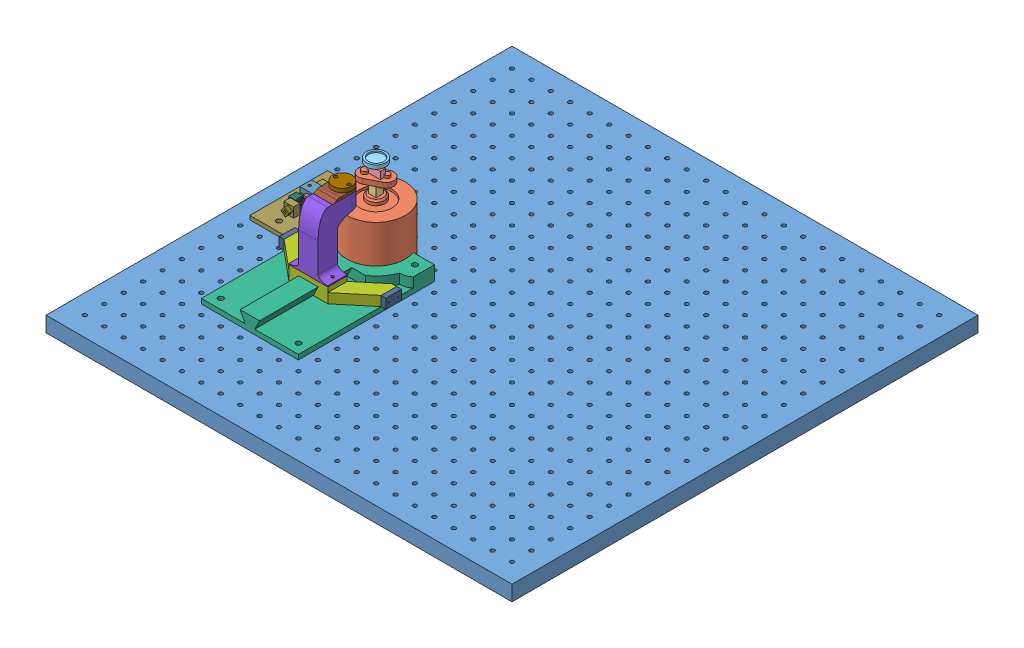
SolidWorks assembly TestAssem, configuration Default. Lengths in mm.
Overall size (609.6 135.55 609.6).
17 component instances, 16 part files, 44 mates.
Components (placement in the parent):
- ThorLabs Table-1: ThorLabs Table [Default] at (-195.0438 -27.549 258.8057) size (609.6 20 609.6)
- Mock Actuator-1: Mock Actuator [Default] at (-42.6438 60.951 -20.5943) x (0.450754 0 0.892648) z (0 -1 0) size (76.15 76.15 99.5)
- Load Cell Connector-1: Load Cell Connector [Default] at (-42.6438 66.951 -20.5943) x (1 0 0) z (0 1 0) size (10 10 12)
- S-Load Cell-1: S-Load Cell [Default] at (-42.6438 88.476 -23.8963) size (17.53 19.05 6.6)
- Top Plate-1: Top Plate [Default] at (-42.6438 106.001 -20.5943) x (-0.837896 0 -0.54583) z (-0.54583 0 0.837896) size (25 10 25)
- Rigid Mount-1: Rigid Mount [Default] at (-42.6438 -7.549 55.6057) size (127 19.05 177.8)
- RigidSlider-1: RigidSlider [Default] at (-42.6438 8.326 42.5829) size (127 19.05 52.07)
- RigidSliderTop-1: RigidSliderTop [Default] at (-42.6438 9.596 42.5829) size (50.93 77.63 58.7)
- rigidspacer5mm-1: rigidspacer5mm [Default] at (-42.643 98.496 23.5329) x (0 1 0) z (-1 0 0) size (5 25 25)
- ElasticClip-2: ElasticClip [Default] at (27.2062 -1.199 15.9129) x (0 0 1) z (-1 0 0) size (20.32 12.7 6.35)
- RigidSliderTopplate-1: RigidSliderTopplate [Default] at (-42.6438 9.596 42.5829) size (25.46 3.21 38.1)
- elasticmount-1: elasticmount [Default] at (-144.2438 -7.549 -33.2943) x (0 0 -1) z (0 1 0) size (101.6 50.8 17.78)
- 1375K102_MXL Series Timing Belt Pulley-1: 1375K102_MXL Series Timing Belt Pulley [1375K102] at (-144.2438 3.881 -24.8993) x (0 0 1) z (-0.408317 0.91284 0) size (17.5 10.8 10.8)
- AxleClutch-1: AxleClutch [Default] at (-144.2438 3.881 -42.8193) x (0 0 1) z (0 1 0) size (15.24 25.4 6.35)
- Elastic Press-1: Elastic Press [Default] at (-144.2438 3.881 -25.8692) size (9.53 12.06 10.18)
- Elastic Handle-1: Elastic Handle [Default] at (-144.2438 3.881 -7.8943) x (-0.581532 -0.813524 0) z (-0.813524 0.581532 0) size (7.84 5.08 7.84)
- ElasticClip-3: ElasticClip [Default] at (-112.4938 -1.199 36.2329) x (0 0 -1) z (1 0 0) size (20.32 12.7 6.35)
Mates (geometry in assembly coordinates):
- Coincident1: coincident anti-aligned: plane of ThorLabs Table-1 through (-195.0438 -7.549 258.8057) normal (0 1 0); plane of Mock Actuator-1 through (-42.6438 -7.549 -20.5943) normal (0 -1 0)
- Coincident2: coincident anti-aligned: plane of Mock Actuator-1 through (-42.6438 66.951 -20.5943) normal (0 1 0); plane of Load Cell Connector-1 through (-42.6438 66.951 -20.5943) normal (0 -1 0)
- Concentric1: concentric aligned: circle of Mock Actuator-1; circle of Load Cell Connector-1
- Parallel1: parallel aligned: plane of ThorLabs Table-1 through (-195.0438 -7.549 258.8057) normal (-1 0 0); plane of Load Cell Connector-1 through (-47.6438 78.951 -25.5943) normal (-1 0 0)
- Coincident4: coincident anti-aligned: plane of Load Cell Connector-1 through (-42.6438 78.951 -20.5943) normal (0 1 0); plane of S-Load Cell-1 through (-33.8808 78.951 -17.2923) normal (0 -1 0)
- Concentric2: concentric anti-aligned: circle of Load Cell Connector-1; circle of S-Load Cell-1
- Parallel2: parallel aligned: plane of Load Cell Connector-1 through (-37.6438 78.951 -25.5943) normal (0 0 -1); plane of S-Load Cell-1 through (-42.6438 88.476 -23.8963) normal (0 0 -1)
- Concentric3: concentric anti-aligned: cylinder of S-Load Cell-1 through (-42.6438 98.001 -20.5943) axis (0 1 0) radius 1.25; cylinder of Top Plate-1 through (-42.6438 103.001 -20.5943) axis (0 -1 0) radius 1.5
- Coincident7: coincident anti-aligned: plane of S-Load Cell-1 through (-33.8808 98.001 -17.2923) normal (0 1 0); plane of Top Plate-1 through (-42.6438 98.001 -20.5943) normal (0 -1 0)
- Coincident8: coincident anti-aligned: plane of ThorLabs Table-1 through (-195.0438 -7.549 258.8057) normal (0 1 0); plane of Rigid Mount-1 through (-42.6438 -7.549 55.6057) normal (0 -1 0)
- Concentric4: concentric aligned: cylinder of Mock Actuator-1 through (-42.6438 -7.549 -20.5943) axis (0 1 0) radius 38.075; cylinder of Rigid Mount-1 through (-42.6438 -7.549 -20.5943) axis (0 1 0) radius 38.1
- Concentric5: concentric aligned: circle of ThorLabs Table-1; circle of Rigid Mount-1
- Concentric6: concentric aligned: circle of ThorLabs Table-1; circle of Rigid Mount-1
- Coincident9: coincident anti-aligned: plane of Rigid Mount-1 through (-42.6438 -1.199 55.6057) normal (0 1 0); plane of RigidSlider-1 through (-17.2438 -1.199 67.9829) normal (0 -1 0)
- Parallel3: parallel aligned: plane of Rigid Mount-1 through (20.8562 -1.199 144.5057) normal (0 0 1); plane of RigidSlider-1 through (-42.6438 8.326 67.9829) normal (0 0 1)
- Coincident12: coincident aligned: plane of RigidSlider-1 through (-68.0438 -1.199 67.9829) normal (-1 0 0); plane of RigidSliderTop-1 through (-68.0438 0.071 67.9829) normal (-1 0 0)
- Coincident13: coincident anti-aligned: plane of RigidSlider-1 through (-17.2438 17.851 67.9829) normal (0 1 0); plane of RigidSliderTop-1 through (-42.6438 17.851 42.5829) normal (0 -1 0)
- Coincident14: coincident aligned: plane of RigidSlider-1 through (-42.6438 8.326 67.9829) normal (0 0 1); plane of RigidSliderTop-1 through (-42.6438 9.596 67.9829) normal (0 0 1)
- Width1: width anti-aligned: plane of RigidSlider-1 through (-68.0438 -1.199 67.9829) normal (-1 0 0); plane of Rigid Mount-1 through (-17.2438 -1.199 67.9829) normal (1 0 0); plane of RigidSlider-1 through (20.8562 -1.199 144.5057) normal (1 0 0); plane of Rigid Mount-1 through (-106.1438 -1.199 144.5057) normal (-1 0 0)
- Concentric7: concentric aligned: circle of RigidSliderTop-1; circle of rigidspacer5mm-1
- Coincident20: coincident anti-aligned: plane of RigidSlider-1 through (20.8562 11.501 36.2329) normal (1 0 0); plane of ElasticClip-2 through (20.8562 -1.199 15.9129) normal (-1 0 0)
- Coincident21: coincident aligned: plane of ElasticClip-2 through (20.8562 11.501 15.9129) normal (0 1 0); plane of RigidSlider-1 through (-42.6438 11.501 42.5829) normal (0 1 0)
- Coincident22: coincident: line of RigidSlider-1 through (20.8562 11.501 36.2329) axis (0 -1 0); plane of ElasticClip-2 through (20.8562 -1.199 36.2329) normal (0 0 1)
- Coincident23: coincident anti-aligned: plane of RigidSliderTop-1 through (-42.6438 95.321 42.5829) normal (0 1 0); plane of RigidSliderTopplate-1 through (-29.9438 95.321 42.5829) normal (0 -1 0)
- Coincident24: coincident anti-aligned: cylinder of RigidSliderTop-1 through (-51.333 92.071 23.5329) axis (0 1 0) radius 2.1526; circle of RigidSliderTopplate-1
- Coincident25: coincident aligned: plane of RigidSliderTop-1 through (-55.3438 95.321 42.5829) normal (-1 0 0); plane of RigidSliderTopplate-1 through (-55.3438 95.321 42.5829) normal (-1 0 0)
- Concentric15: concentric aligned: cylinder of rigidspacer5mm-1 through (-51.333 98.496 23.5329) axis (0 -1 0) radius 2.1526; cylinder of RigidSliderTopplate-1 through (-51.333 174.696 23.5329) axis (0 -1 0) radius 2.1526
- Coincident26: coincident anti-aligned: plane of rigidspacer5mm-1 through (-42.643 98.496 23.5329) normal (0 -1 0); plane of RigidSliderTopplate-1 through (-29.9438 98.496 42.5829) normal (0 1 0)
- Coincident27: coincident aligned: cylinder of rigidspacer5mm-1 through (-33.953 98.496 23.5329) axis (0 -1 0) radius 2.1526; circle of RigidSliderTopplate-1
- Coincident28: coincident anti-aligned: plane of ThorLabs Table-1 through (-195.0438 -7.549 258.8057) normal (0 1 0); plane of elasticmount-1 through (-144.2438 -7.549 -33.2943) normal (0 -1 0)
- Parallel5: parallel aligned: plane of ThorLabs Table-1 through (-195.0438 -7.549 258.8057) normal (-1 0 0); plane of elasticmount-1 through (-169.6438 -2.469 -84.0943) normal (-1 0 0)
- Concentric16: concentric aligned: circle of ThorLabs Table-1; circle of elasticmount-1
- Concentric17: concentric anti-aligned: cylinder of elasticmount-1 through (-144.2438 3.881 -20.5943) axis (0 0 1) radius 1.5; cylinder of 1375K102_MXL Series Timing Belt Pulley-1 through (-144.2438 3.881 -33.6493) axis (0 0 -1) radius 1.5
- Coincident30: coincident anti-aligned: plane of elasticmount-1 through (-150.5938 10.231 -16.1493) normal (0 0 -1); plane of 1375K102_MXL Series Timing Belt Pulley-1 through (-149.1731 1.6761 -16.1493) normal (0 0 1)
- Coincident31: coincident anti-aligned: plane of elasticmount-1 through (-144.2438 3.881 -35.1993) normal (0 1 0); plane of AxleClutch-1 through (-144.2438 3.881 -42.8193) normal (0 -1 0)
- Coincident32: coincident aligned: plane of elasticmount-1 through (-144.2438 -7.549 -35.1993) normal (0 0 1); plane of AxleClutch-1 through (-156.9438 10.231 -35.1993) normal (0 0 1)
- Coincident33: coincident aligned: plane of elasticmount-1 through (-156.9438 -7.549 -33.2943) normal (-1 0 0); plane of AxleClutch-1 through (-156.9438 10.231 -35.1993) normal (-1 0 0)
- Coincident34: coincident anti-aligned: plane of elasticmount-1 through (-144.2438 -2.469 -33.2943) normal (0 1 0); plane of Elastic Press-1 through (-144.2438 -2.469 -18.8692) normal (0 -1 0)
- Concentric19: concentric aligned: cylinder of 1375K102_MXL Series Timing Belt Pulley-1 through (-144.2438 3.881 -33.6493) axis (0 0 -1) radius 5.4; cylinder of Elastic Press-1 through (-144.2438 3.881 -18.8692) axis (0 0 -1) radius 3.4
- Concentric20: concentric anti-aligned: cylinder of elasticmount-1 through (-144.2438 3.881 -20.5943) axis (0 0 1) radius 1.5; cylinder of Elastic Handle-1 through (-144.2438 3.881 -2.8143) axis (0 0 -1) radius 1.5
- Coincident36: coincident anti-aligned: plane of elasticmount-1 through (-150.5938 10.231 -7.8943) normal (0 0 1); plane of Elastic Handle-1 through (-144.2438 3.881 -7.8943) normal (0 0 -1)
- Coincident37: coincident anti-aligned: plane of RigidSlider-1 through (-106.1438 11.501 36.2329) normal (-1 0 0); plane of ElasticClip-3 through (-106.1438 -1.199 36.2329) normal (1 0 0)
- Coincident38: coincident aligned: plane of RigidSlider-1 through (-42.6438 11.501 42.5829) normal (0 1 0); plane of ElasticClip-3 through (-106.1438 11.501 36.2329) normal (0 1 0)
- Coincident40: coincident: line of RigidSlider-1 through (-106.1438 11.501 36.2329) axis (0 -1 0); plane of ElasticClip-3 through (-106.1438 -1.199 36.2329) normal (0 0 1)
